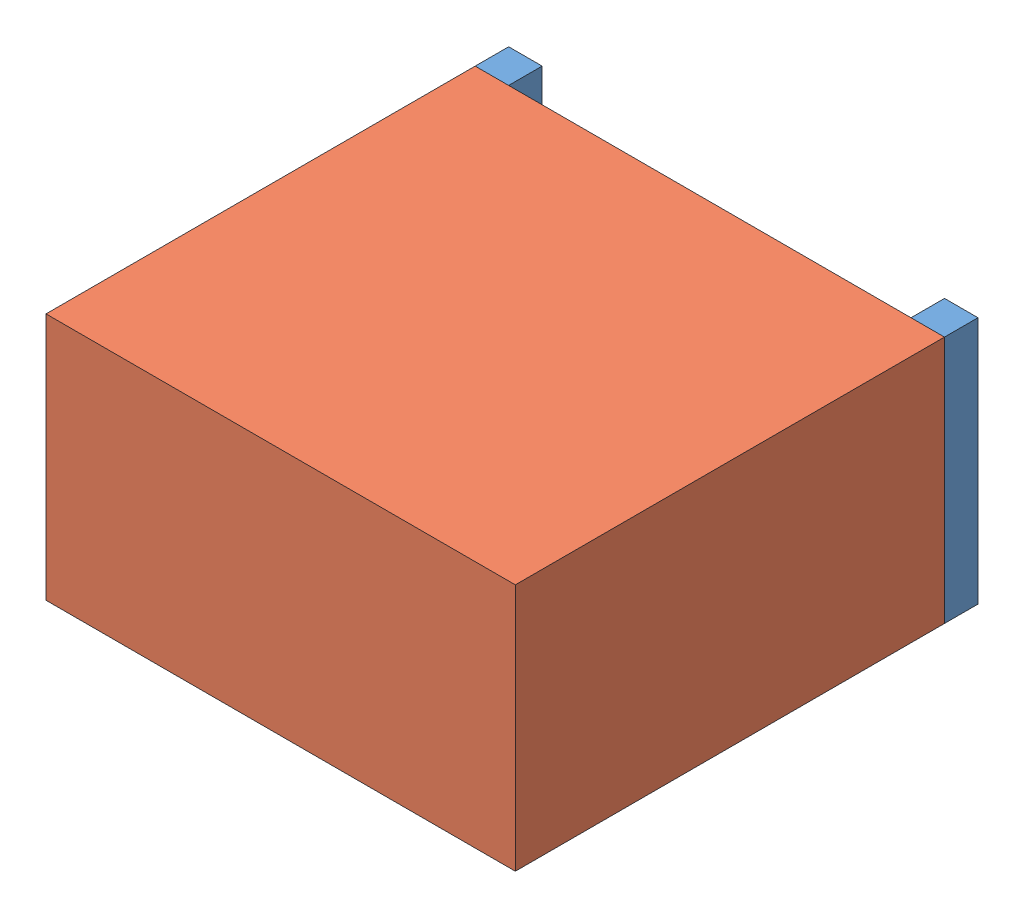
SolidWorks assembly PCC-1_2-R, configuration Default. Lengths in mm.
Overall size (8.89 4.7 8.76).
6 component instances, 2 part files, 0 mates.
Components (placement in the parent):
- 8134220976-1: 8134220976 [Default] at (4.1274 -0.0001 -0.635) size (0.63 4.7 0.64)
  - Extruded_61-1: Extruded_61 [Default] at origin size (0.63 4.7 0.64)
- 8134220976-2: 8134220976 [Default] at (-4.1276 -0.0001 -0.635) size (0.63 4.7 0.64)
  - Extruded_61-1: Extruded_61 [Default] at origin size (0.63 4.7 0.64)
- 8134220576-1: 8134220576 [Default] at origin size (8.89 4.7 8.13)
  - Extruded_62-1: Extruded_62 [Default] at origin size (8.89 4.7 8.13)
